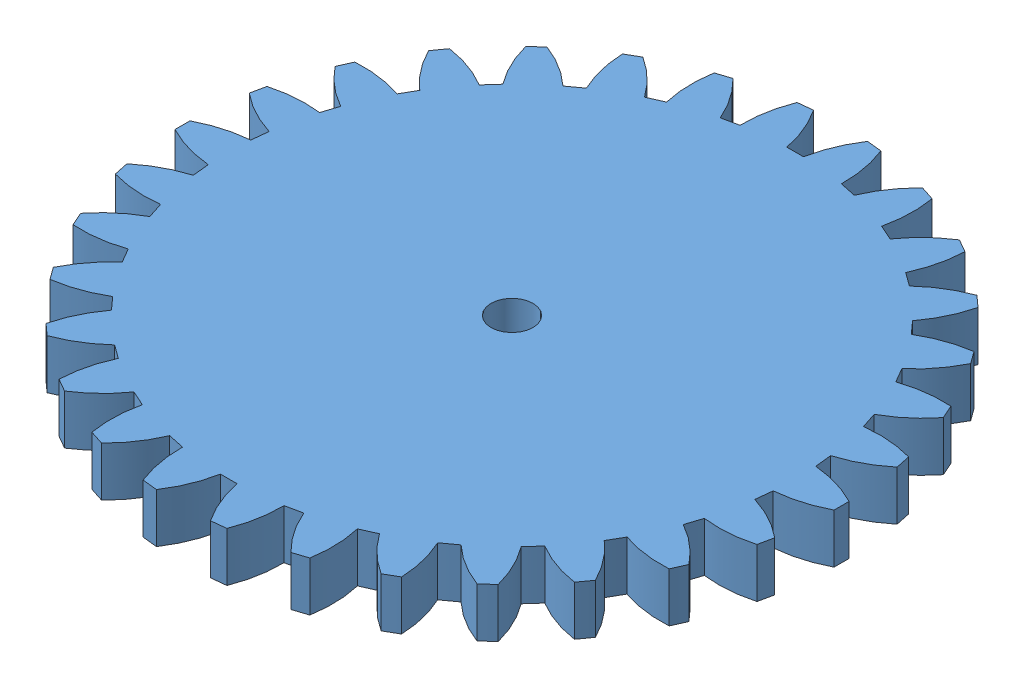
SolidWorks assembly gear_horn, configuration Default. Lengths in mm.
Overall size (40 7.23 40).
2 component instances, 2 part files, 2 mates.
Components (placement in the parent):
- claw_gear-1: claw_gear [30T 1.0Mod] at (11.9426 18.2851 23.4866) size (40 3 40)
- Micro Servo Horn Single Arm-1: Micro Servo Horn Single Arm [Default] at (11.9426 16.6722 23.4866) x (0.880546 0 0.473961) z (-0.473961 0 0.880546) size (19.74 4.23 7.24)
Mates (geometry in assembly coordinates):
- Coincident1: coincident anti-aligned: plane of claw_gear-1 through (11.9426 18.2851 23.4866) normal (0 -1 0); plane of Micro Servo Horn Single Arm-1 through (11.9426 18.2851 23.4866) normal (0 1 0)
- Concentric1: concentric anti-aligned: circle of claw_gear-1; circle of Micro Servo Horn Single Arm-1
